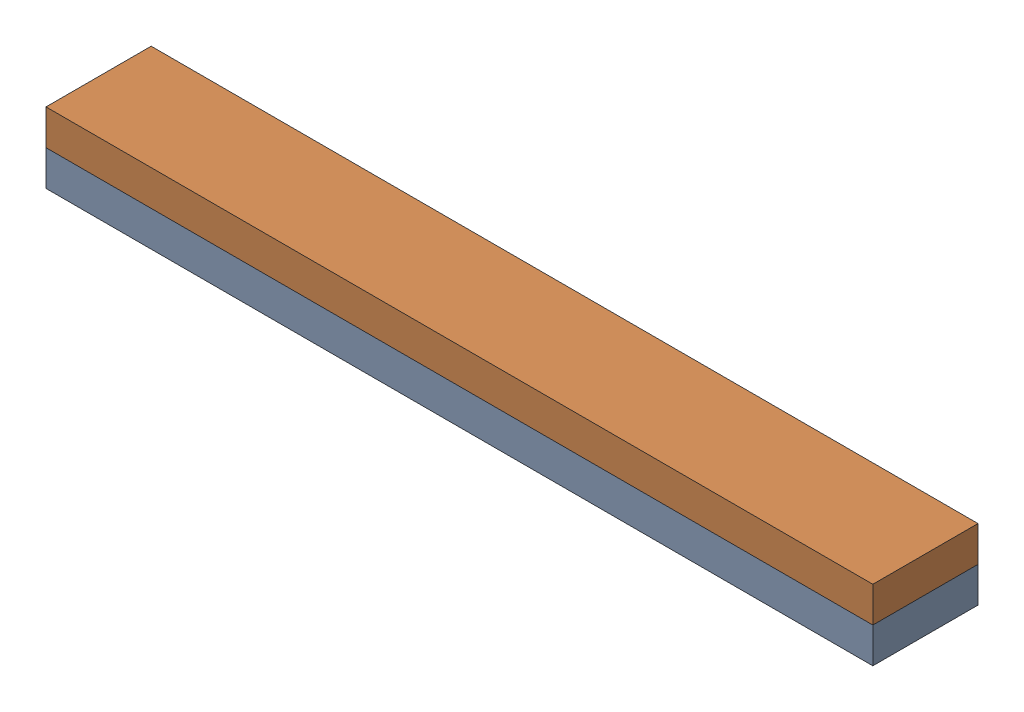
SolidWorks assembly Ножка, configuration По умолчанию. Lengths in mm.
Overall size (515 44 65.5).
2 component instances, 1 part files, 3 mates.
Components (placement in the parent):
- Доска515_22ПЛ-1: Доска515_22ПЛ [По умолчанию] at origin size (515 22 65.5)
- Доска515_22ПЛ-2: Доска515_22ПЛ [По умолчанию] at (0 22 0) size (515 22 65.5)
Mates (geometry in assembly coordinates):
- Совпадение6: coincident aligned: plane of Доска515_22ПЛ-1 through (-257.5 0 -2) normal (0 0 1); plane of Доска515_22ПЛ-2 through (-257.5 22 -2) normal (0 0 1)
- Совпадение4: coincident anti-aligned: plane of Доска515_22ПЛ-1 through (0 22 0) normal (0 1 0); plane of Доска515_22ПЛ-2 through (0 22 -23) normal (0 -1 0)
- Совпадение5: coincident aligned: plane of Доска515_22ПЛ-1 through (-257.5 22 -67.5) normal (-1 0 0); plane of Доска515_22ПЛ-2 through (-257.5 44 -90.5) normal (-1 0 0)
